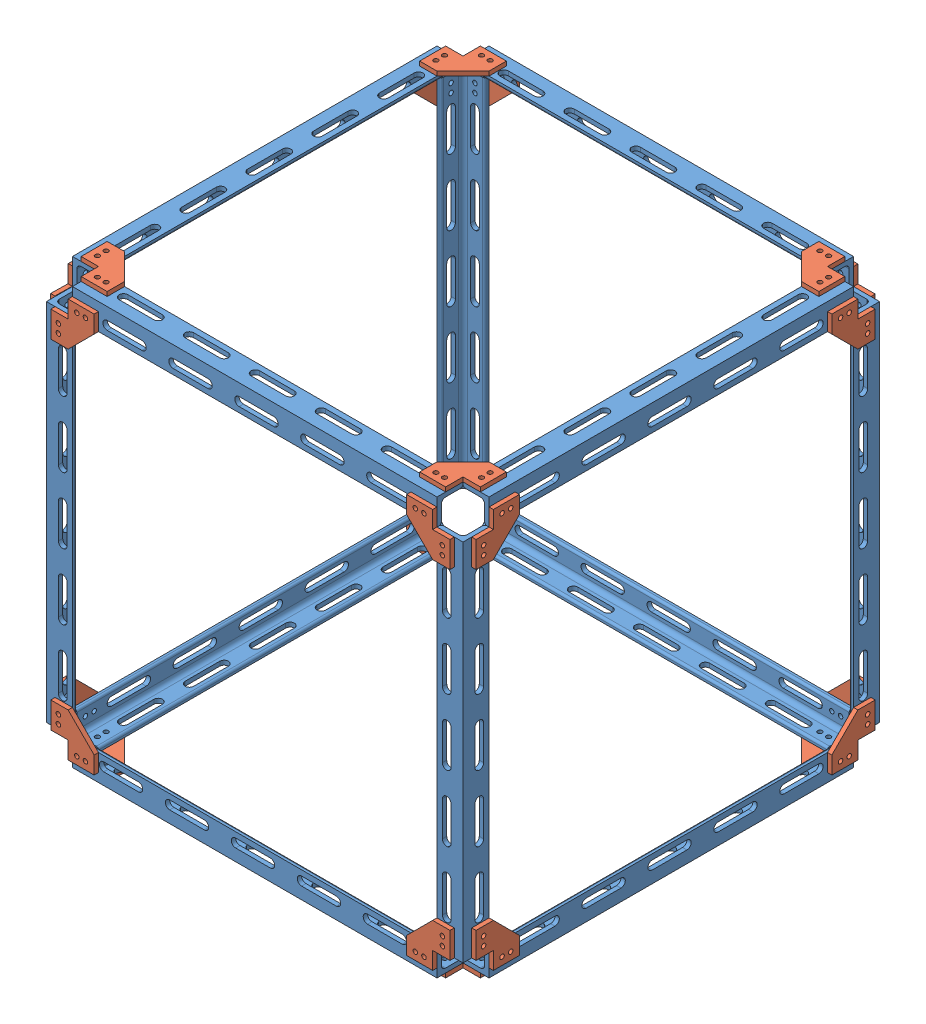
SolidWorks assembly Outer struct 12 in side length, configuration Default. Lengths in mm.
Overall size (311.15 311.15 311.15).
36 component instances, 2 part files, 64 mates.
Components (placement in the parent):
- WIP 12 inch .75 L rod-1: WIP 12 inch .75 L rod [8982K281] at (-9.525 9.525 0) size (19.05 19.05 266.7)
- WIP bracket for .75 L bar-1: WIP bracket for .75 L bar [Default] at (-44.4499 -3.175 -146.0502) x (1 0 0.000006) z (-0.000006 0 1) size (31.75 3.17 31.75)
- WIP 12 inch .75 L rod-2: WIP 12 inch .75 L rod [8982K281] at (-152.4002 9.525 -142.8755) x (0 0 -1) z (1 0 0) size (19.05 19.05 266.7)
- WIP 12 inch .75 L rod-3: WIP 12 inch .75 L rod [8982K281] at (-9.525 152.3996 -142.8755) x (1 0 0) z (0 -1 0) size (19.05 19.05 266.7)
- WIP bracket for .75 L bar-2: WIP bracket for .75 L bar [Default] at (0 44.4494 -146.0507) x (0 -1 0.000022) z (0 0.000022 1) size (31.75 3.17 31.75)
- WIP bracket for .75 L bar-3: WIP bracket for .75 L bar [Default] at (-44.4504 6.3501 -152.4005) x (1 -0.000015 0) z (0.000015 1 0) size (31.75 3.17 31.75)
- WIP bracket for .75 L bar-4: WIP bracket for .75 L bar [Default] at (-260.3502 298.4499 -152.4005) x (-1 0 0) z (0 -1 0) size (31.75 3.17 31.75)
- WIP bracket for .75 L bar-5: WIP bracket for .75 L bar [Default] at (-304.8002 260.35 -146.0506) x (0 1 0.000002) z (0 -0.000002 1) size (31.75 3.17 31.75)
- WIP bracket for .75 L bar-6: WIP bracket for .75 L bar [Default] at (-260.3502 307.9748 -146.0505) x (-1 0 0) z (0 0 1) size (31.75 3.17 31.75)
- WIP 12 inch .75 L rod-4: WIP 12 inch .75 L rod [8982K281] at (-152.4002 295.2748 -142.8755) x (0 0 -1) z (-1 0 0) size (19.05 19.05 266.7)
- WIP 12 inch .75 L rod-5: WIP 12 inch .75 L rod [8982K281] at (-295.2752 295.2748 -0.0005) x (-1 0 0) z (0 0 1) size (19.05 19.05 266.7)
- WIP 12 inch .75 L rod-6: WIP 12 inch .75 L rod [8982K281] at (-295.2752 152.3999 -142.8755) x (-1 0 0) z (0 1 0) size (19.05 19.05 266.7)
- WIP bracket for .75 L bar-8: WIP bracket for .75 L bar [Default] at (-6.3503 260.3499 -152.4005) x (0.000002 1 0) z (-1 0.000002 0) size (31.75 3.17 31.75)
- WIP bracket for .75 L bar-9: WIP bracket for .75 L bar [Default] at (-298.4502 44.4499 -152.4005) x (0 -1 0) z (1 0 0) size (31.75 3.17 31.75)
- WIP bracket for .75 L bar-11: WIP bracket for .75 L bar [Default] at (-6.3505 304.8004 107.9491) x (0.000026 0 1) z (-1 0 0.000026) size (31.75 3.17 31.75)
- WIP bracket for .75 L bar-12: WIP bracket for .75 L bar [Default] at (-44.4496 298.4506 152.3997) x (1 -0.000013 0) z (-0.000013 -1 0) size (31.75 3.17 31.75)
- WIP 12 inch .75 L rod-7: WIP 12 inch .75 L rod [8982K281] at (-152.3996 295.2754 142.8747) x (0 0 1) z (1 0 0) size (19.05 19.05 266.7)
- WIP 12 inch .75 L rod-8: WIP 12 inch .75 L rod [8982K281] at (-9.525 295.2748 -0.0008) x (0 1 0) z (0 0 1) size (19.05 19.05 266.7)
- WIP bracket for .75 L bar-13: WIP bracket for .75 L bar [Default] at (3.175 298.4493 107.9491) x (0 0.000026 1) z (0 -1 0.000026) size (31.75 3.17 31.75)
- WIP 12 inch .75 L rod-9: WIP 12 inch .75 L rod [8982K281] at (-9.525 152.4002 142.8747) x (0 0 1) z (0 -1 0) size (19.05 19.05 266.7)
- WIP bracket for .75 L bar-14: WIP bracket for .75 L bar [Default] at (3.175 260.3496 -146.0505) x (0 1 -0.000009) z (0 0.000009 1) size (31.75 3.17 31.75)
- WIP bracket for .75 L bar-15: WIP bracket for .75 L bar [Default] at (-298.4499 307.9754 107.9499) x (0.000007 0 1) z (1 0 -0.000007) size (31.75 3.17 31.75)
- WIP bracket for .75 L bar-16: WIP bracket for .75 L bar [Default] at (-44.4503 304.7998 -146.0503) x (1 0 -0.000013) z (0.000013 0 1) size (31.75 3.17 31.75)
- WIP bracket for .75 L bar-17: WIP bracket for .75 L bar [Default] at (-6.3497 -3.175 107.9497) x (0.000002 0 1) z (-1 0 0.000002) size (31.75 3.17 31.75)
- WIP bracket for .75 L bar-18: WIP bracket for .75 L bar [Default] at (3.175 44.4503 146.0496) x (0 -1 0.000013) z (0 -0.000013 -1) size (31.75 3.17 31.75)
- WIP bracket for .75 L bar-19: WIP bracket for .75 L bar [Default] at (-298.4492 260.3501 152.3997) x (-0.000013 1 0) z (1 0.000013 0) size (31.75 3.17 31.75)
- WIP bracket for .75 L bar-20: WIP bracket for .75 L bar [Default] at (-304.8002 298.2273 107.8544) x (0 0.017459 0.999848) z (0 -0.999848 0.017459) size (31.75 3.17 31.75)
- WIP bracket for .75 L bar-21: WIP bracket for .75 L bar [Default] at (-304.7994 44.4499 146.0495) x (0 -1 0) z (0 0 -1) size (31.75 3.17 31.75)
- WIP 12 inch .75 L rod-11: WIP 12 inch .75 L rod [8982K281] at (-295.2744 152.4002 142.8747) x (-1 0 0) z (0 -1 0) size (19.05 19.05 266.7)
- WIP bracket for .75 L bar-22: WIP bracket for .75 L bar [Default] at (-260.3497 6.3497 152.3997) x (-1 0.000013 0) z (0.000013 1 0) size (31.75 3.17 31.75)
- WIP 12 inch .75 L rod-12: WIP 12 inch .75 L rod [8982K281] at (-152.3996 9.525 142.8747) x (0 0 1) z (-1 0 0) size (19.05 19.05 266.7)
- WIP bracket for .75 L bar-23: WIP bracket for .75 L bar [Default] at (-260.3497 -3.175 146.05) x (-1 0 -0.000013) z (0.000013 0 -1) size (31.75 3.17 31.75)
- WIP 12 inch .75 L rod-13: WIP 12 inch .75 L rod [8982K281] at (-295.2744 9.525 -0.0004) x (-1 0 0) z (0 0 -1) size (19.05 19.05 266.7)
- WIP bracket for .75 L bar-24: WIP bracket for .75 L bar [Default] at (-304.8002 6.35 -107.9505) x (0 -0.000004 -1) z (0 1 -0.000004) size (31.75 3.17 31.75)
- WIP bracket for .75 L bar-25: WIP bracket for .75 L bar [Default] at (-298.4495 -3.175 -107.95) x (-0.000022 0 -1) z (1 0 -0.000022) size (31.75 3.17 31.75)
- WIP bracket for .75 L bar-26: WIP bracket for .75 L bar [Default] at (-6.3501 44.4503 152.3997) x (0.000013 -1 0) z (-1 -0.000013 0) size (31.75 3.17 31.75)
Mates (geometry in assembly coordinates):
- Coincident45: coincident anti-aligned: circle of WIP .75 L rod-2; circle of WIP bracket for .75 L bar-3
- Coincident46: coincident anti-aligned: circle of WIP .75 L rod-3; circle of WIP bracket for .75 L bar-3
- Coincident47: coincident aligned: circle of WIP .75 L rod-1; circle of WIP bracket for .75 L bar-1
- Coincident48: coincident aligned: circle of WIP bracket for .75 L bar-1; circle of WIP .75 L rod-2
- Coincident49: coincident anti-aligned: circle of WIP .75 L rod-1; circle of WIP bracket for .75 L bar-2
- Coincident50: coincident anti-aligned: circle of WIP .75 L rod-3; circle of WIP bracket for .75 L bar-2
- Coincident51: coincident anti-aligned: circle of WIP .75 L rod-6; circle of WIP bracket for .75 L bar-9
- Coincident52: coincident aligned: circle of WIP bracket for .75 L bar-6; circle of WIP .75 L rod-5
- Coincident53: coincident aligned: circle of WIP bracket for .75 L bar-6; circle of WIP .75 L rod-4
- Coincident54: coincident anti-aligned: circle of WIP bracket for .75 L bar-4; circle of WIP .75 L rod-4
- Coincident55: coincident anti-aligned: circle of WIP bracket for .75 L bar-4; circle of WIP .75 L rod-6
- Coincident56: coincident anti-aligned: circle of WIP bracket for .75 L bar-5; circle of WIP .75 L rod-6
- Coincident57: coincident anti-aligned: circle of WIP bracket for .75 L bar-5; circle of WIP .75 L rod-5
- Coincident58: coincident aligned: circle of WIP bracket for .75 L bar-6; circle of WIP .75 L rod-5
- Coincident59: coincident aligned: circle of WIP bracket for .75 L bar-6; circle of WIP .75 L rod-4
- Coincident61: coincident anti-aligned: circle of WIP .75 L rod-2; circle of WIP bracket for .75 L bar-9
- Coincident62: coincident anti-aligned: circle of WIP .75 L rod-4; circle of WIP bracket for .75 L bar-8
- Coincident63: coincident anti-aligned: circle of WIP .75 L rod-3; circle of WIP bracket for .75 L bar-8
- Coincident64: coincident anti-aligned: circle of WIP bracket for .75 L bar-12; circle of WIP .75 L rod-7
- Coincident65: coincident anti-aligned: circle of WIP bracket for .75 L bar-11; circle of WIP .75 L rod-7
- Coincident66: coincident aligned: circle of WIP .75 L rod-8; circle of WIP bracket for .75 L bar-13
- Coincident67: coincident aligned: circle of WIP bracket for .75 L bar-13; circle of WIP .75 L rod-9
- Coincident68: coincident anti-aligned: circle of WIP bracket for .75 L bar-12; circle of WIP .75 L rod-9
- Coincident69: coincident anti-aligned: circle of WIP bracket for .75 L bar-11; circle of WIP .75 L rod-8
- Coincident70: coincident aligned: circle of WIP .75 L rod-3; circle of WIP bracket for .75 L bar-14
- Coincident71: coincident aligned: circle of WIP .75 L rod-8; circle of WIP bracket for .75 L bar-14
- Coincident72: coincident anti-aligned: circle of WIP .75 L rod-8; circle of WIP bracket for .75 L bar-16
- Coincident73: coincident anti-aligned: circle of WIP .75 L rod-4; circle of WIP bracket for .75 L bar-16
- Coincident74: coincident aligned: circle of WIP .75 L rod-7; circle of WIP bracket for .75 L bar-15
- Coincident76: coincident aligned: circle of WIP .75 L rod-5; circle of WIP bracket for .75 L bar-15
- Coincident77: coincident anti-aligned: circle of WIP .75 L rod-5; circle of WIP bracket for .75 L bar-20
- Coincident78: coincident anti-aligned: circle of WIP .75 L rod-7; circle of WIP bracket for .75 L bar-19
- Coincident79: coincident aligned: circle of WIP .75 L rod-1; circle of WIP bracket for .75 L bar-18
- Coincident80: coincident aligned: circle of WIP .75 L rod-9; circle of WIP bracket for .75 L bar-18
- Coincident81: coincident anti-aligned: circle of WIP bracket for .75 L bar-21; circle of WIP .75 L rod-11
- Coincident82: coincident anti-aligned: circle of WIP .75 L rod-11; circle of WIP bracket for .75 L bar-22
- Coincident83: coincident aligned: circle of WIP .75 L rod-12; circle of WIP bracket for .75 L bar-23
- Coincident84: coincident aligned: circle of WIP bracket for .75 L bar-23; circle of WIP .75 L rod-13
- Coincident85: coincident anti-aligned: circle of WIP bracket for .75 L bar-21; circle of WIP .75 L rod-13
- Coincident86: coincident anti-aligned: circle of WIP bracket for .75 L bar-22; circle of WIP .75 L rod-12
- Coincident87: coincident aligned: circle of WIP .75 L rod-1; circle of WIP bracket for .75 L bar-17
- Coincident88: coincident aligned: circle of WIP bracket for .75 L bar-17; circle of WIP .75 L rod-12
- Coincident89: coincident aligned: circle of WIP .75 L rod-13; circle of WIP bracket for .75 L bar-25
- Coincident91: coincident aligned: circle of WIP .75 L rod-2; circle of WIP bracket for .75 L bar-25
- Coincident92: coincident anti-aligned: circle of WIP .75 L rod-6; circle of WIP bracket for .75 L bar-24
- Coincident93: coincident anti-aligned: circle of WIP .75 L rod-13; circle of WIP bracket for .75 L bar-24
- Coincident94: coincident anti-aligned: circle of WIP .75 L rod-12; circle of WIP bracket for .75 L bar-26
- Coincident95: coincident anti-aligned: circle of WIP .75 L rod-9; circle of WIP bracket for .75 L bar-26
- Coincident96: coincident anti-aligned: circle of WIP bracket for .75 L bar-19; circle of WIP .75 L rod-11
- Coincident98: coincident anti-aligned: circle of WIP .75 L rod-7; circle of WIP bracket for .75 L bar-19
- Coincident100: coordinate: point of WIP 12 inch .75 L rod-1
- Coincident101: coincident anti-aligned: circle of WIP bracket for .75 L bar-4; circle of WIP 12 inch .75 L rod-6
- Coincident102: coincident aligned: circle of WIP bracket for .75 L bar-17; circle of WIP 12 inch .75 L rod-12
- Coincident103: coincident aligned: circle of WIP 12 inch .75 L rod-9; circle of WIP bracket for .75 L bar-18
- Coincident104: coincident aligned: circle of WIP 12 inch .75 L rod-1; circle of WIP bracket for .75 L bar-18
- Coincident105: coincident aligned: circle of WIP bracket for .75 L bar-6; circle of WIP 12 inch .75 L rod-4
- Coincident106: coincident aligned: circle of WIP bracket for .75 L bar-6; circle of WIP 12 inch .75 L rod-5
- Coincident107: coincident anti-aligned: circle of WIP 12 inch .75 L rod-6; circle of WIP bracket for .75 L bar-9
- Coincident108: coincident anti-aligned: circle of WIP 12 inch .75 L rod-8; circle of WIP bracket for .75 L bar-16
- Coincident109: coincident anti-aligned: circle of WIP 12 inch .75 L rod-4; circle of WIP bracket for .75 L bar-16
- Coincident110: coincident anti-aligned: circle of WIP bracket for .75 L bar-22; circle of WIP 12 inch .75 L rod-12
- Coincident111: coincident anti-aligned: circle of WIP 12 inch .75 L rod-2; circle of WIP bracket for .75 L bar-3
- Coincident112: coincident anti-aligned: circle of WIP bracket for .75 L bar-12; circle of WIP 12 inch .75 L rod-7
- Coincident113: coincident anti-aligned: circle of WIP bracket for .75 L bar-12; circle of WIP 12 inch .75 L rod-9
